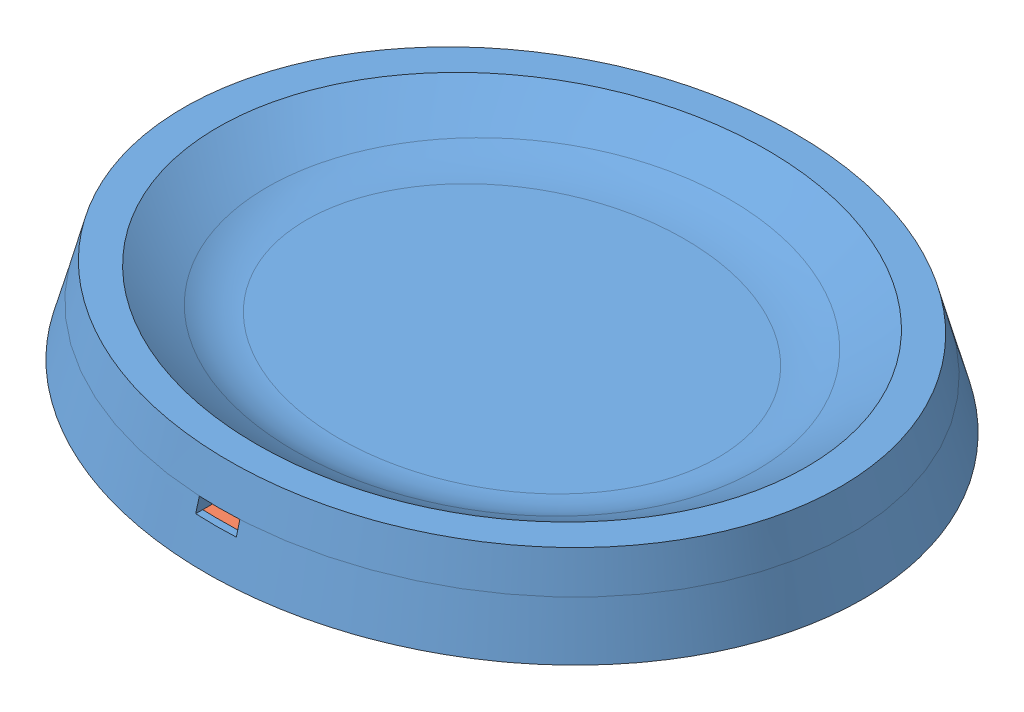
SolidWorks assembly Base_assemble, configuration Default. Lengths in mm.
Overall size (159.78 36.93 139.46).
2 component instances, 2 part files, 3 mates.
Components (placement in the parent):
- Base_up-2: Base_up [Default] at origin size (159.78 36.93 139.46)
- Base_down-3: Base_down [Default] at (0 -25.3826 0) size (158.24 2.6 138)
Mates (geometry in assembly coordinates):
- Coincident1: coincident aligned: plane of Base_up-2 through (0 0 0) normal (1 0 0); plane of Base_down-3 through (0 -25.3826 0) normal (1 0 0)
- Coincident2: coincident aligned: plane of Base_down-3 through (0 -25.3826 0) normal (0 0 1)
- Coincident3: coincident anti-aligned: plane of Base_up-2 through (74.0374 -22.7826 0.1958) normal (0 -1 0); plane of Base_down-3 through (73.4812 -22.7826 6.1456) normal (0 1 0)
